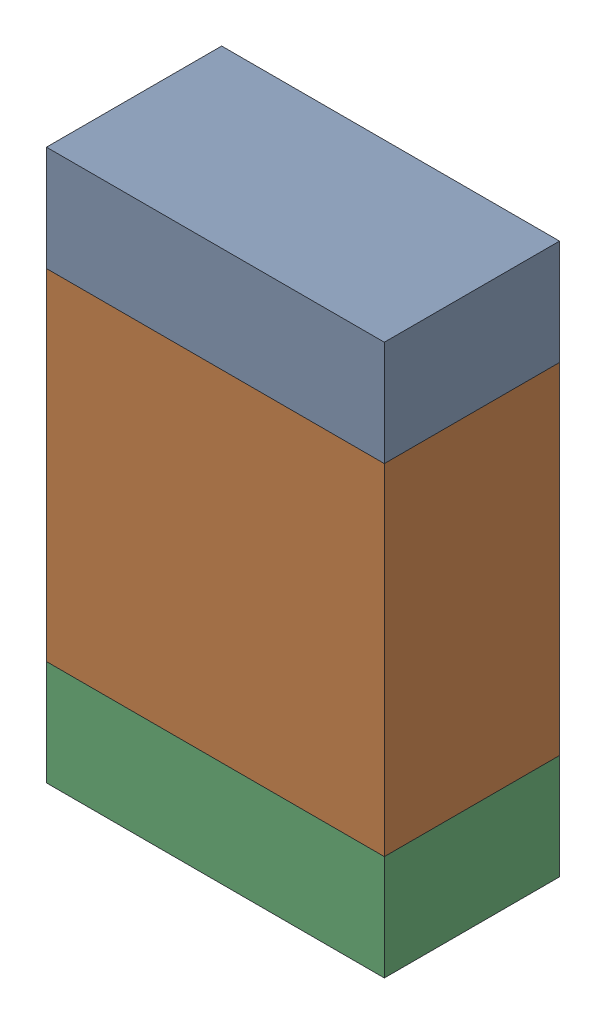
SolidWorks assembly R12, configuration Default. Lengths in mm.
Overall size (1.35 2.2 0.7).
6 component instances, 2 part files, 0 mates.
Components (placement in the parent):
- 959207304-1: 959207304 [Default] at (152.7811 87.2879 0) size (1.35 0.42 0.7)
  - Extruded-8-1: Extruded-8 [Default] at origin size (1.35 0.42 0.7)
- 959207440-1: 959207440 [Default] at (152.7811 86.3979 0) size (1.35 1.36 0.7)
  - Extruded-9-1: Extruded-9 [Default] at origin size (1.35 1.36 0.7)
- 959207304-2: 959207304 [Default] at (152.7811 85.5079 0) size (1.35 0.42 0.7)
  - Extruded-8-1: Extruded-8 [Default] at origin size (1.35 0.42 0.7)
